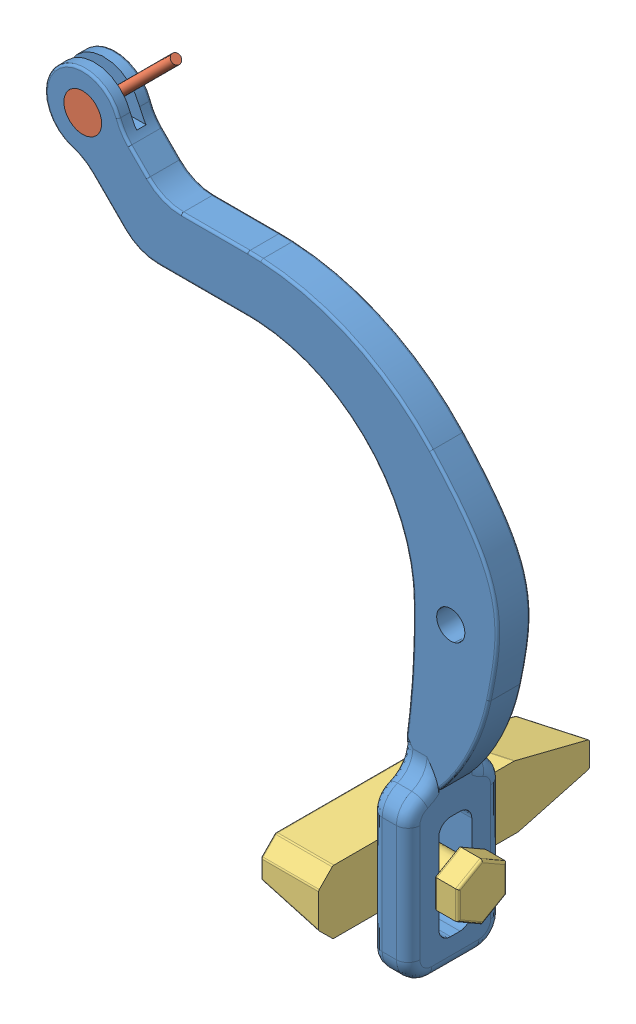
SolidWorks assembly Bicycle Caliper Assembly, configuration Default. Lengths in mm.
Overall size (99.18 137.72 57.44).
3 component instances, 3 part files, 5 mates.
Components (placement in the parent):
- Bicycle Caliper-1: Bicycle Caliper [Default] at (4.0858 96.5413 90.8035) size (99.18 128.75 20)
- Bicycle Brake Wire-1: Bicycle Brake Wire [Default] at (4.0858 96.5413 86.3035) size (20.97 20.97 7)
- Bicycle Brake Pad-1: Bicycle Brake Pad [Default] at (48.5489 -7.4377 87.5535) x (0 0 1) z (-1 0 0) size (57.44 13.44 28)
Mates (geometry in assembly coordinates):
- Concentric1: concentric aligned: circle of Bicycle Caliper-1; circle of Bicycle Brake Wire-1
- Coincident4: coincident aligned: plane of Bicycle Caliper-1 through (4.0858 96.5413 90.8035) normal (0 0 1); plane of Bicycle Brake Wire-1 through (4.0858 96.5413 90.8035) normal (0 0 1)
- Distance1: distance = 4.51 mm: line of Bicycle Brake Pad-1 through (71.5489 -0.7187 105.0416) axis (0 0 -1); plane of Bicycle Caliper-1 through (45.5489 3.7913 90.8035) normal (0 -1 0)
- Tangent3: tangent anti-aligned: plane of Bicycle Caliper-1 through (45.5489 3.7913 90.8035) normal (0 0 -1); cylinder of Bicycle Brake Pad-1 through (71.5489 -7.4377 87.5535) axis (1 0 0) radius 3.25
- Coincident5: coincident anti-aligned: plane of Bicycle Caliper-1 through (71.5489 -24.2087 97.3035) normal (-1 0 0); plane of Bicycle Brake Pad-1 through (71.5489 -7.4377 87.5535) normal (1 0 0)
